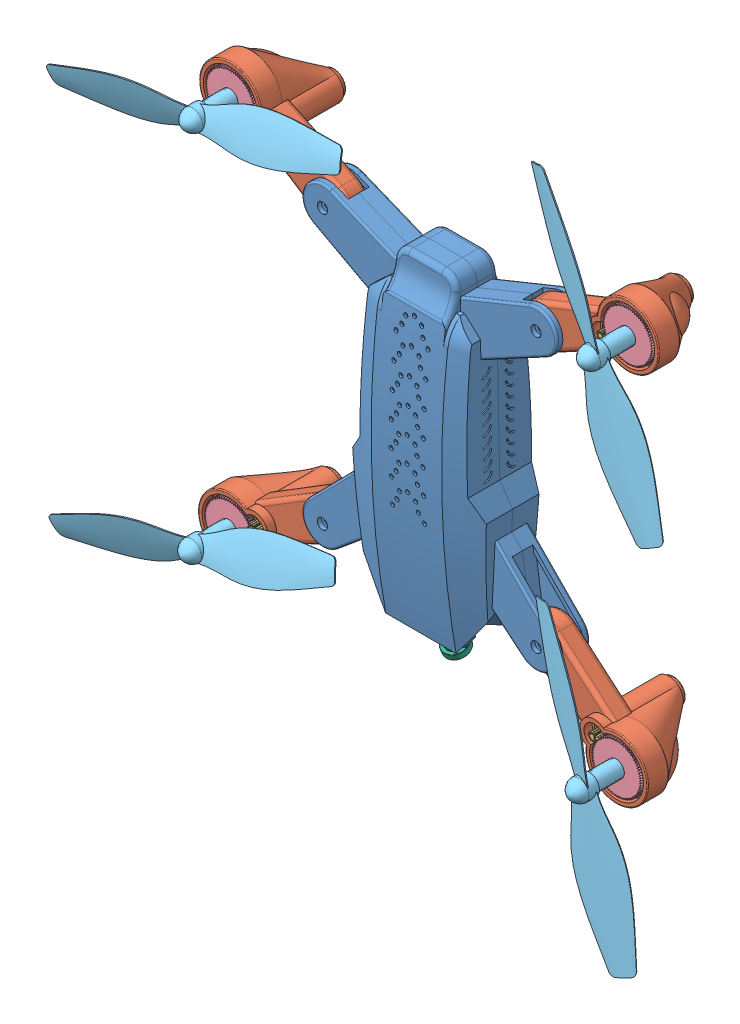
SolidWorks assembly Assem1, configuration Default. Lengths in mm.
Overall size (300.9 325.83 61.7).
18 component instances, 6 part files, 46 mates.
Components (placement in the parent):
- Part1-1: Part1 [Default] x (1 0 0) z (0 0 -1) size (123 168.67 46.01)
- Leg_3-1: Leg_3 [Default] at (91.3559 -89.6912 -1) x (0.797117 -0.603825 0) z (-0.603825 -0.797117 0) size (75.07 38.54 30.07)
- Leg_3-2: Leg_3 [Default] at (96.7789 93.7091 -1) x (0.905577 0.424182 0) z (0.424182 -0.905577 0) size (75.07 38.54 30.07)
- Leg_3-3: Leg_3 [Default] at (-95.5686 -83.1211 -1) x (-0.881373 -0.472422 0) z (-0.472422 0.881373 0) size (75.07 38.54 30.07)
- Leg_3-4: Leg_3 [Default] at (-95.0092 97.1363 -1) x (-0.870184 0.492727 0) z (0.492727 0.870184 0) size (75.07 38.54 30.07)
- Gearing_2-1: Gearing_2 [Default] at (80.5948 -81.5396 -16.1) x (-0.993821 0.110997 0) z (0.110997 0.993821 0) size (8 26.1 8)
- Arm Gear_4-1: Arm Gear_4 [Default] at (91.3559 -89.6912 -11) x (0.275412 -0.961326 0) z (-0.961326 -0.275412 0) size (24 29 23.98)
- Impeller blade_1-1: Impeller blade_1 [Default] at (91.3559 -89.6912 9.2) x (-0.275412 0.961326 0) z (0.961326 0.275412 0) size (144.29 23 19.57)
- Arm Gear_4-2: Arm Gear_4 [Default] at (96.7789 93.7091 -11) x (0.99152 -0.129952 0) z (-0.129952 -0.99152 0) size (24 29 23.98)
- Gearing_2-2: Gearing_2 [Default] at (84.5536 87.9826 -16.1) x (-0.790521 0.612434 0) z (0.612434 0.790521 0) size (8 26.1 8)
- Impeller blade_1-2: Impeller blade_1 [Default] at (-95.5686 -83.1211 9.2) x (0.942113 0.335296 0) z (0.335296 -0.942113 0) size (144.29 23 19.57)
- Impeller blade_1-3: Impeller blade_1 [Default] at (96.7789 93.7091 9.2) x (-0.383218 0.923658 0) z (0.923658 0.383218 0) size (144.29 23 19.57)
- Gearing_2-3: Gearing_2 [Default] at (-83.6701 -76.7434 -16.1) x (-0.898439 -0.439098 0) z (-0.439098 0.898439 0) size (8 26.1 8)
- Gearing_2-4: Gearing_2 [Default] at (-83.2617 90.4845 -16.1) x (-0.573123 0.819469 0) z (0.819469 0.573123 0) size (8 26.1 8)
- Arm Gear_4-3: Arm Gear_4 [Default] at (-95.5686 -83.1211 -11) x (0.942113 0.335296 0) z (0.335296 -0.942113 0) size (24 29 23.98)
- Arm Gear_4-4: Arm Gear_4 [Default] at (-95.0092 97.1363 -11) x (0.283857 0.958867 0) z (0.958867 -0.283857 0) size (24 29 23.98)
- Impeller blade_1-5: Impeller blade_1 [Default] at (-95.0092 97.1363 9.2) x (0.972331 0.233606 0) z (0.233606 -0.972331 0) size (144.29 23 19.57)
- Camera_5-1: Camera_5 [Default] at (0 -79 0) x (0 0.384615 -0.923077) z (-1 0 0) size (11 15 22.5)
Mates (geometry in assembly coordinates):
- Coincident1: coincident anti-aligned: plane of Part1-1 through (0 0 0) normal (0 0 -1); plane of assembly through (0 0 0) normal (0 0 1)
- Coincident2: coincident anti-aligned: plane of Part1-1 through (0 0 0) normal (0 -1 0); plane of assembly through (0 0 0) normal (0 1 0)
- Coincident3: coincident aligned: plane of Part1-1; plane of assembly through (0 0 0) normal (1 0 0)
- Concentric1: concentric anti-aligned: cylinder of Part1-1 through (51.5 -59.5 8) axis (0 0 -1) radius 2.5; cylinder of Leg_3-1 through (51.5 -59.5 -5) axis (0 0 1) radius 2.5
- Width1: width aligned: plane of Part1-1 through (51.5 -59.5 -5) normal (0 0 1); plane of Part1-1 through (51.5 -59.5 5) normal (0 0 -1); plane of Leg_3-1 through (91.3559 -89.6912 5) normal (0 0 1); plane of Leg_3-1 through (91.3559 -89.6912 -5) normal (0 0 -1)
- Concentric2: concentric anti-aligned: cylinder of Part1-1 through (51.5 72.5 8) axis (0 0 -1) radius 2.5; cylinder of Leg_3-2 through (51.5 72.5 -5) axis (0 0 1) radius 2.5
- Width2: width aligned: plane of Part1-1 through (51.5 72.5 -5) normal (0 0 1); plane of Part1-1 through (51.5 72.5 5) normal (0 0 -1); plane of Leg_3-2 through (96.7789 93.7091 5) normal (0 0 1); plane of Leg_3-2 through (96.7789 93.7091 -5) normal (0 0 -1)
- Concentric3: concentric anti-aligned: cylinder of Part1-1 through (-51.5 -59.5 8) axis (0 0 -1) radius 2.5; cylinder of Leg_3-3 through (-51.5 -59.5 -5) axis (0 0 1) radius 2.5
- Width3: width anti-aligned: plane of Part1-1 through (-51.5 -59.5 5) normal (0 0 -1); plane of Part1-1 through (-51.5 -59.5 -5) normal (0 0 1); plane of Leg_3-3 through (-95.5686 -83.1211 5) normal (0 0 1); plane of Leg_3-3 through (-95.5686 -83.1211 -5) normal (0 0 -1)
- Concentric4: concentric anti-aligned: cylinder of Part1-1 through (-51.5 72.5 8) axis (0 0 -1) radius 2.5; cylinder of Leg_3-4 through (-51.5 72.5 -5) axis (0 0 1) radius 2.5
- Width4: width anti-aligned: plane of Part1-1 through (-51.5 72.5 5) normal (0 0 -1); plane of Part1-1 through (-51.5 72.5 -5) normal (0 0 1); plane of Leg_3-4 through (-95.0092 97.1363 5) normal (0 0 1); plane of Leg_3-4 through (-95.0092 97.1363 -5) normal (0 0 -1)
- Concentric5: concentric anti-aligned: cylinder of Leg_3-1 through (91.3559 -89.6912 -11) axis (0 0 1) radius 4; cylinder of Arm Gear_4-1 through (91.3559 -89.6912 -11) axis (0 0 -1) radius 3
- Coincident5: coincident aligned: plane of Leg_3-1 through (85.9753 -85.6154 9) normal (0 0 1); plane of Arm Gear_4-1 through (92.1821 -92.5752 9) normal (0 0 1)
- Concentric6: concentric anti-aligned: cylinder of Leg_3-1 through (80.5948 -81.5396 -17) axis (0 0 1) radius 4; cylinder of Gearing_2-1 through (80.5948 -81.5396 -16.1) axis (0 0 -1) radius 4
- Distance1: distance = 1 mm aligned: plane of Gearing_2-1 through (80.5948 -81.5396 10) normal (0 0 1); plane of Arm Gear_4-1 through (92.1821 -92.5752 9) normal (0 0 1)
- GearMate5: gear = 70 : 11 mm: cylinder of Gearing_2-1 through (80.5948 -81.5396 -16.1) axis (0 0 -1) radius 4; cylinder of Arm Gear_4-1 through (91.3559 -89.6912 -11) axis (0 0 -1) radius 3
- Concentric7: concentric aligned: cylinder of Arm Gear_4-1 through (91.3559 -89.6912 -11) axis (0 0 -1) radius 3; cylinder of Impeller blade_1-1 through (91.3559 -89.6912 9.2) axis (0 0 -1) radius 4
- Coincident6: coincident anti-aligned: plane of Arm Gear_4-1 through (89.3501 -91.7673 0.5147) normal (-0.24215 -0.970239 0); plane of Impeller blade_1-1 through (92.1509 -92.4663 18) normal (0.24215 0.970239 0)
- Coincident7: coincident anti-aligned: plane of Arm Gear_4-1 through (91.3559 -89.6912 18) normal (0 0 1); plane of Impeller blade_1-1 through (91.3559 -89.6912 18) normal (0 0 -1)
- Concentric8: concentric anti-aligned: cylinder of Leg_3-2 through (96.7789 93.7091 -11) axis (0 0 1) radius 4; cylinder of Arm Gear_4-2 through (96.7789 93.7091 -11) axis (0 0 -1) radius 3
- Coincident8: coincident aligned: plane of Leg_3-2 through (90.6662 90.8459 9) normal (0 0 1); plane of Arm Gear_4-2 through (99.7534 93.3192 9) normal (0 0 1)
- Concentric9: concentric anti-aligned: cylinder of Leg_3-2 through (84.5536 87.9826 -17) axis (0 0 1) radius 4; cylinder of Gearing_2-2 through (84.5536 87.9826 -16.1) axis (0 0 -1) radius 4
- Distance2: distance = 1 mm aligned: plane of Gearing_2-2 through (84.5536 87.9826 10) normal (0 0 1); plane of Arm Gear_4-2 through (99.7534 93.3192 9) normal (0 0 1)
- GearMate10: gear = 70 : 11 mm: cylinder of Gearing_2-2 through (84.5536 87.9826 -16.1) axis (0 0 -1) radius 4; cylinder of Arm Gear_4-2 through (96.7789 93.7091 -11) axis (0 0 -1) radius 3
- Concentric10: concentric aligned: cylinder of Arm Gear_4-2 through (96.7789 93.7091 -11) axis (0 0 -1) radius 3; cylinder of Impeller blade_1-3 through (96.7789 93.7091 9.2) axis (0 0 -1) radius 4
- Coincident9: coincident anti-aligned: plane of Arm Gear_4-2 through (97.8851 91.0427 0.5147) normal (0.793706 -0.608302 0); plane of Impeller blade_1-3 through (99.6411 93.3339 18) normal (-0.793706 0.608302 0)
- Coincident10: coincident anti-aligned: plane of Arm Gear_4-2 through (96.7789 93.7091 18) normal (0 0 1); plane of Impeller blade_1-3 through (96.7789 93.7091 18) normal (0 0 -1)
- Concentric11: concentric anti-aligned: cylinder of Leg_3-3 through (-83.6701 -76.7434 -17) axis (0 0 1) radius 4; cylinder of Gearing_2-3 through (-83.6701 -76.7434 -16.1) axis (0 0 -1) radius 4
- Concentric12: concentric anti-aligned: cylinder of Leg_3-3 through (-95.5686 -83.1211 -11) axis (0 0 1) radius 4; cylinder of Arm Gear_4-3 through (-95.5686 -83.1211 -11) axis (0 0 -1) radius 3
- Coincident11: coincident aligned: plane of Leg_3-3 through (-89.6194 -79.9322 9) normal (0 0 1); plane of Arm Gear_4-3 through (-92.7423 -82.1152 9) normal (0 0 1)
- Distance3: distance = 1 mm aligned: plane of Gearing_2-3 through (-83.6701 -76.7434 10) normal (0 0 1); plane of Arm Gear_4-3 through (-92.7423 -82.1152 9) normal (0 0 1)
- GearMate11: gear = 70 : 11 mm: cylinder of Gearing_2-3 through (-83.6701 -76.7434 -16.1) axis (0 0 -1) radius 4; cylinder of Arm Gear_4-3 through (-95.5686 -83.1211 -11) axis (0 0 -1) radius 3
- Concentric13: concentric anti-aligned: cylinder of Leg_3-4 through (-83.2617 90.4845 -17) axis (0 0 1) radius 4; cylinder of Gearing_2-4 through (-83.2617 90.4845 -16.1) axis (0 0 -1) radius 4
- Concentric14: concentric anti-aligned: cylinder of Leg_3-4 through (-95.0092 97.1363 -11) axis (0 0 1) radius 4; cylinder of Arm Gear_4-4 through (-95.0092 97.1363 -11) axis (0 0 -1) radius 3
- Coincident12: coincident aligned: plane of Leg_3-4 through (-89.1355 93.8104 9) normal (0 0 1); plane of Arm Gear_4-4 through (-94.1576 100.0129 9) normal (0 0 1)
- Distance4: distance = 1 mm aligned: plane of Gearing_2-4 through (-83.2617 90.4845 10) normal (0 0 1); plane of Arm Gear_4-4 through (-94.1576 100.0129 9) normal (0 0 1)
- GearMate13: gear = 70 : 11 mm: cylinder of Gearing_2-4 through (-83.2617 90.4845 -16.1) axis (0 0 -1) radius 4; cylinder of Arm Gear_4-4 through (-95.0092 97.1363 -11) axis (0 0 -1) radius 3
- Concentric15: concentric aligned: cylinder of Arm Gear_4-4 through (-95.0092 97.1363 -11) axis (0 0 -1) radius 3; cylinder of Impeller blade_1-5 through (-95.0092 97.1363 9.2) axis (0 0 -1) radius 4
- Coincident13: coincident anti-aligned: plane of Arm Gear_4-4 through (-96.9967 99.23 0.5147) normal (-0.958867 0.283857 0); plane of Impeller blade_1-5 through (-97.8161 96.462 18) normal (0.958867 -0.283857 0)
- Coincident14: coincident anti-aligned: plane of Arm Gear_4-4 through (-95.0092 97.1363 18) normal (0 0 1); plane of Impeller blade_1-5 through (-95.0092 97.1363 18) normal (0 0 -1)
- Concentric16: concentric aligned: cylinder of Impeller blade_1-2 through (-95.5686 -83.1211 9.2) axis (0 0 -1) radius 4; cylinder of Arm Gear_4-3 through (-95.5686 -83.1211 -11) axis (0 0 -1) radius 3
- Coincident15: coincident anti-aligned: plane of Impeller blade_1-2 through (-98.2883 -84.089 18) normal (0.983542 -0.180682 0); plane of Arm Gear_4-3 through (-97.7667 -81.2498 0.5147) normal (-0.983542 0.180682 0)
- Coincident16: coincident anti-aligned: plane of Impeller blade_1-2 through (-95.5686 -83.1211 18) normal (0 0 -1); plane of Arm Gear_4-3 through (-95.5686 -83.1211 18) normal (0 0 1)
- Coincident20: coincident anti-aligned: plane of Part1-1 through (9.25 -12.6479 30.355) normal (-1 0 0); plane of Camera_5-1 through (9.25 -79.8462 -5.7692) normal (1 0 0)
- Concentric19: concentric aligned: cylinder of Part1-1 through (61.5 -79.9231 -0.3846) axis (-1 0 0) radius 0.75; cylinder of Camera_5-1 through (11.25 -79.9231 -0.3846) axis (-1 0 0) radius 0.75
- Width5: width anti-aligned: plane of Part1-1 through (0 -12.6479 30.355) normal (0 -0.384615 0.923077); plane of Part1-1 through (0 -10.7249 25.7396) normal (0 0.384615 -0.923077); plane of Camera_5-1 through (0 -77.0769 -4.6154) normal (0 0.384615 -0.923077); plane of Camera_5-1 through (0 -80.9231 4.6154) normal (0 -0.384615 0.923077)
